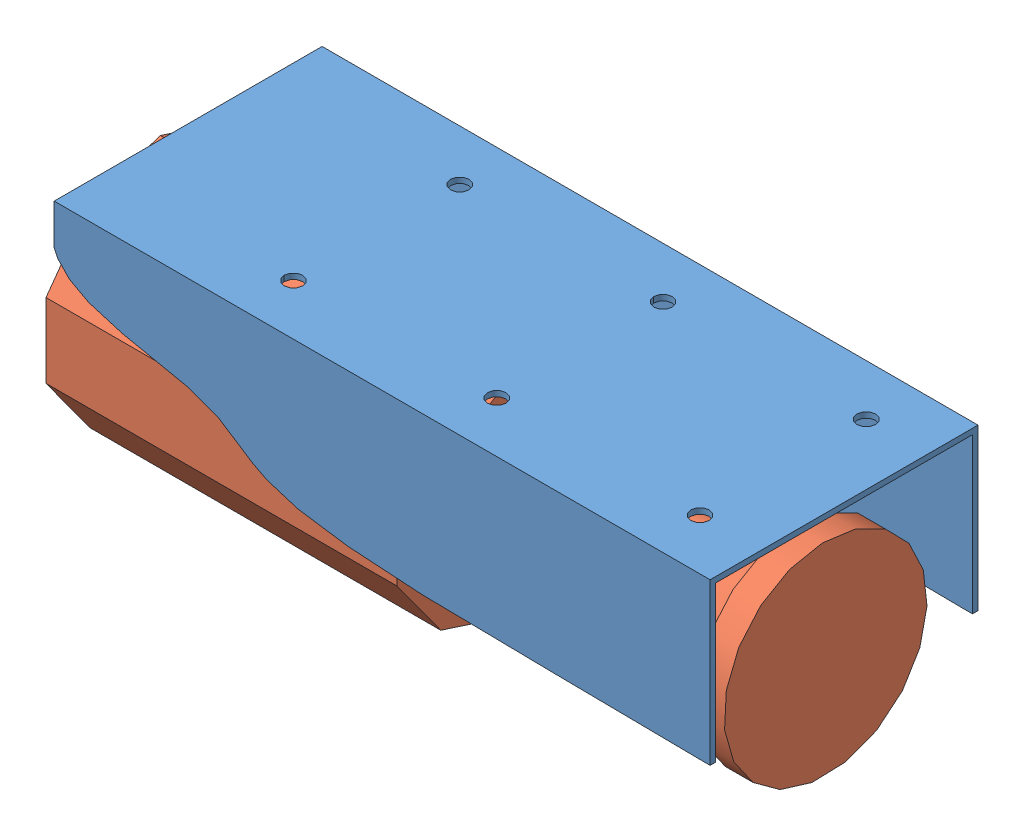
SolidWorks assembly Таль, configuration По умолчанию. Lengths in mm.
Overall size (370 154.15 153.95).
2 component instances, 2 part files, 3 mates.
Components (placement in the parent):
- Корпус-1: Корпус [По умолчанию] at (284.4202 283.1335 283.2806) size (355 91.57 145)
- Катушка-1: Катушка [По умолчанию] at (459.4202 292.0251 210.8024) x (0 0.976522 -0.215418) z (0 -0.215418 -0.976522) size (127.16 360 129.6)
Mates (geometry in assembly coordinates):
- Расстояние1: distance = 10 mm: plane of Катушка-1 through (629.4202 303.8731 264.5111) normal (1 0 0); plane of Корпус-1 through (639.4202 283.1335 283.2806) normal (1 0 0)
- Расстояние2: distance = 7.6 mm: plane of Катушка-1 through (269.4202 312.1447 148.8806) normal (0 0 -1); plane of Корпус-1 through (639.4202 370.1335 141.2806) normal (0 0 1)
- Расстояние3: distance = 10 mm: line of Катушка-1 through (269.4202 357.1335 210.8024) axis (1 0 0); plane of Корпус-1 through (639.4202 367.1335 283.2806) normal (0 -1 0)
